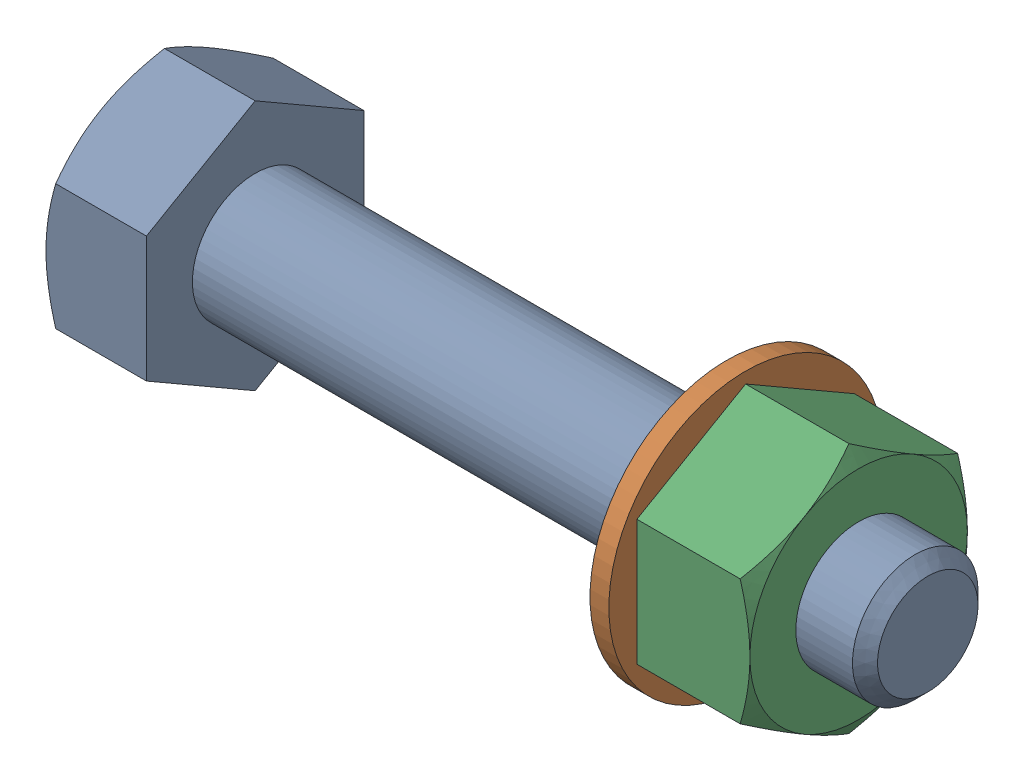
SolidWorks assembly screw_nut_washer_asseme_test, configuration Default. Lengths in mm.
Overall size (172.4 70 72.75).
3 component instances, 3 part files, 4 mates.
Components (placement in the parent):
- Screw-1: Screw [Default] at (-84.8672 8.6636 -5.2889) size (172.4 56 48.5)
- washer-1: washer [Default] at (24.5069 8.6636 -5.2889) size (4.2 61 61)
- nut-1: nut [Default] at (49.7069 8.6636 -5.2889) x (1 0 0) z (0 0.866025 0.5) size (25.2 56 48.5)
Mates (geometry in assembly coordinates):
- Concentric1: concentric anti-aligned: cylinder of Screw-1 through (65.1328 8.6636 -5.2889) axis (-1 0 0) radius 14; cylinder of washer-1 through (20.3069 8.6636 -5.2889) axis (1 0 0) radius 14.5
- Concentric2: concentric anti-aligned: cylinder of Screw-1 through (65.1328 8.6636 -5.2889) axis (-1 0 0) radius 14; cylinder of nut-1 through (24.5069 8.6636 -5.2889) axis (1 0 0) radius 14
- Coincident1: coincident anti-aligned: plane of washer-1 through (24.5069 8.6636 -5.2889) normal (1 0 0); plane of nut-1 through (24.5069 8.6636 -5.2889) normal (-1 0 0)
- Parallel1: parallel aligned: plane of Screw-1 through (-107.2672 22.6636 -29.5376) normal (0 0.866025 -0.5); plane of nut-1 through (24.5069 22.6636 -29.5376) normal (0 0.866025 -0.5)
